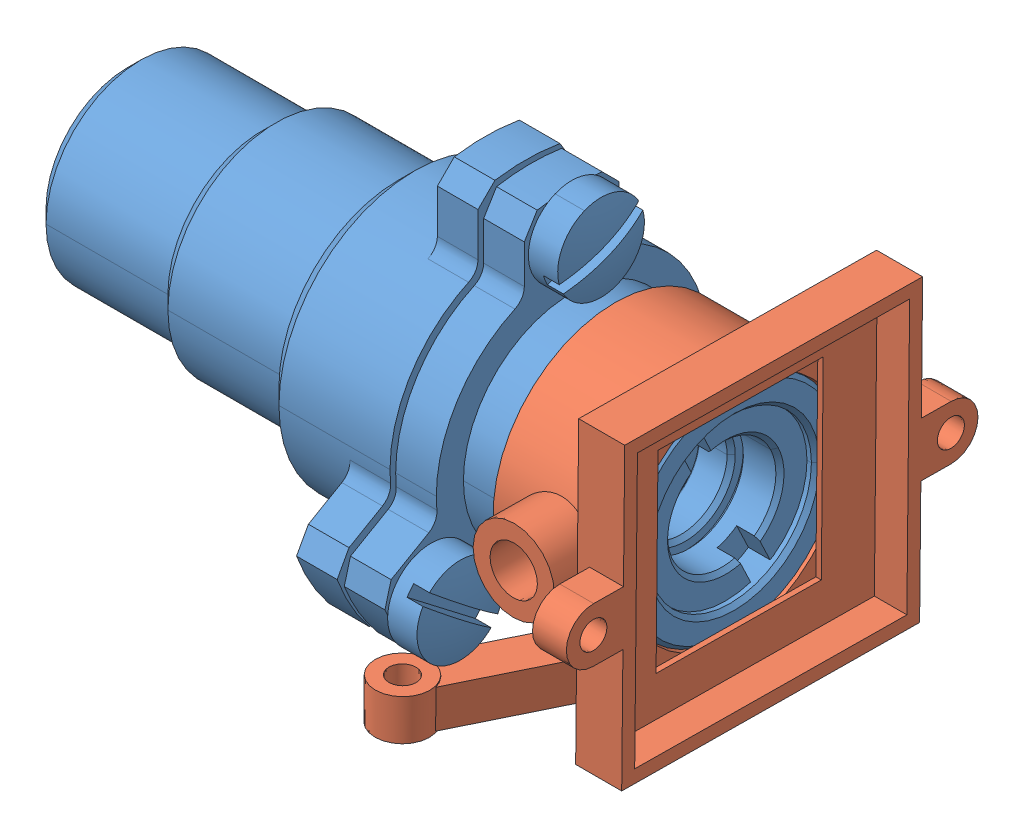
SolidWorks assembly 装配体1, configuration 默认. Lengths in mm.
Overall size (23.81 13.93 15.32).
2 component instances, 2 part files, 2 mates.
Components (placement in the parent):
- Microscope-00.step-1: Microscope-00.step [默认] at origin size (22.41 12.6 13.9)
- cmos外壳v5-1: cmos外壳v5 [默认] at (17.0558 0 0) x (0 -0.010132 -0.999949) z (0 -0.999949 0.010132) size (15.2 8 11.75)
Mates (geometry in assembly coordinates):
- 同心1: concentric aligned: cylinder of Microscope-00.step-1 through (7.1615 0 0) axis (-1 0 0) radius 4; cylinder of cmos外壳v5-1 through (33.2755 0 0) axis (-1 0 0) radius 4.0375
- 重合1: coincident anti-aligned: plane of Microscope-00.step-1 through (21.8558 3 0) normal (1 0 0); plane of cmos外壳v5-1 through (21.8558 0 0) normal (-1 0 0)
